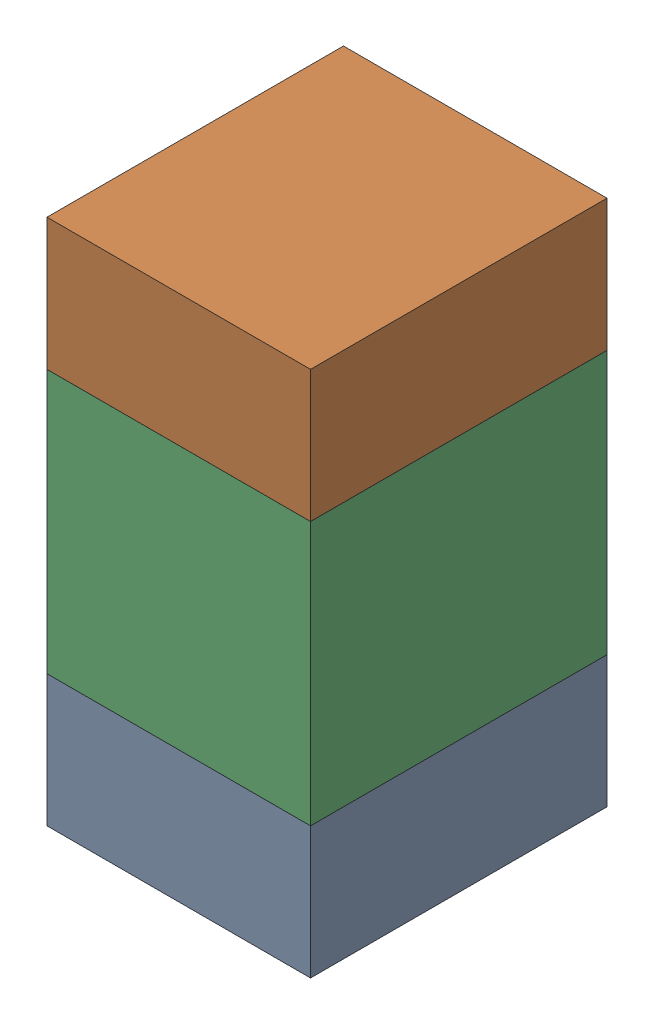
SolidWorks assembly C8, configuration ﾃﾞﾌｫﾙﾄ. Lengths in mm.
Overall size (0.8 1.6 0.9).
6 component instances, 2 part files, 0 mates.
Components (placement in the parent):
- 689259880-1: 689259880 [ﾃﾞﾌｫﾙﾄ] at (64.7499 51.9001 0) size (0.8 0.4 0.9)
  - Extruded_5-1: Extruded_5 [ﾃﾞﾌｫﾙﾄ] at origin size (0.8 0.4 0.9)
- 689259880-2: 689259880 [ﾃﾞﾌｫﾙﾄ] at (64.7499 53.1001 0) size (0.8 0.4 0.9)
  - Extruded_5-1: Extruded_5 [ﾃﾞﾌｫﾙﾄ] at origin size (0.8 0.4 0.9)
- 689259608-1: 689259608 [ﾃﾞﾌｫﾙﾄ] at (64.7499 52.5 0) size (0.8 0.8 0.9)
  - Extruded_3-1: Extruded_3 [ﾃﾞﾌｫﾙﾄ] at origin size (0.8 0.8 0.9)
